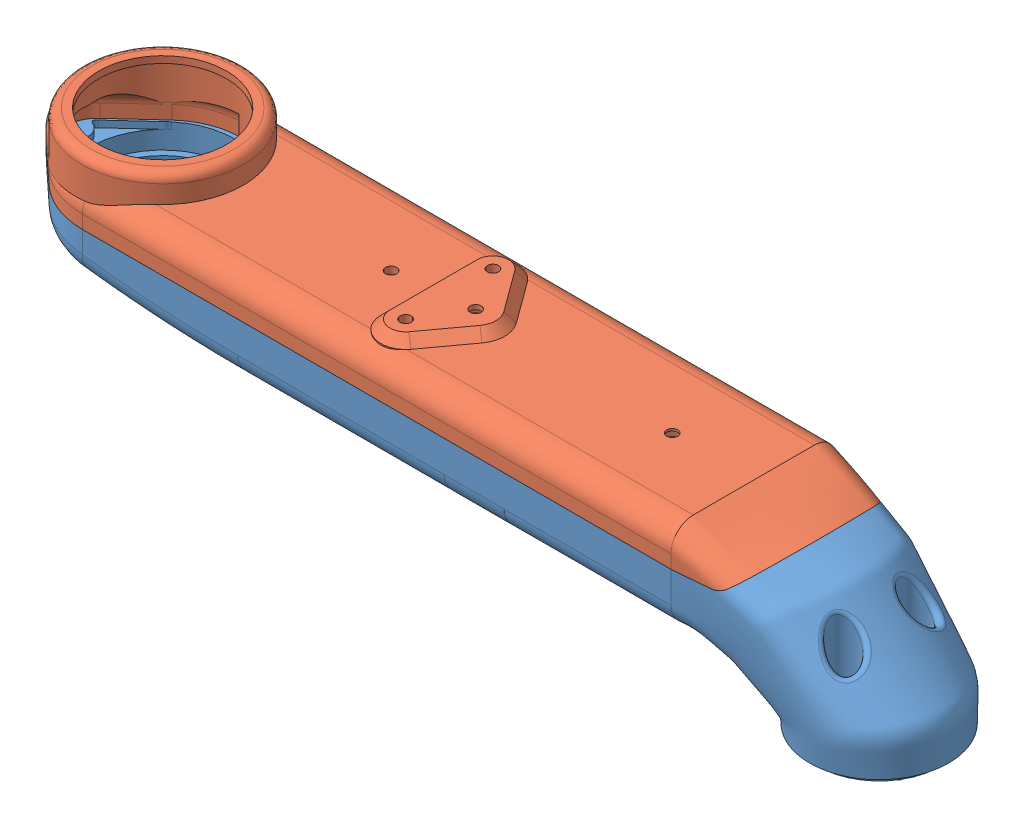
SolidWorks assembly upper leg module, configuration Default. Lengths in mm.
Overall size (198.25 43.5 37.06).
2 component instances, 2 part files, 3 mates.
Components (placement in the parent):
- upper leg module shell base-1: upper leg module shell base [Default] at (64.5696 101.4754 134.999) x (0 0 1) z (-1 0 0) size (37.02 37.51 198.25)
- upper leg module cover-1: upper leg module cover [Default] at (58.1988 107.4754 134.999) size (170.23 17.96 37.06)
Mates (geometry in assembly coordinates):
- Coincident1: coincident anti-aligned: plane of upper leg module shell base-1 through (24.5696 107.4754 153.499) normal (0 1 0); plane of Part1-1 through (58.1988 107.4754 134.999) normal (0 -1 0)
- Coincident2: coincident: line of upper leg module shell base-1 through (4.1397 107.4754 153.499) axis (1 0 0); plane of Part1-1 through (135.5688 115.4754 153.499) normal (0 0 1)
- Coincident4: coincident anti-aligned: plane of upper leg module shell base-1 through (95.0825 65.1116 116.4949) normal (-0.642788 0.766044 0); plane of Part1-1 through (94.2983 64.4537 116.449) normal (0.642788 -0.766044 0)
